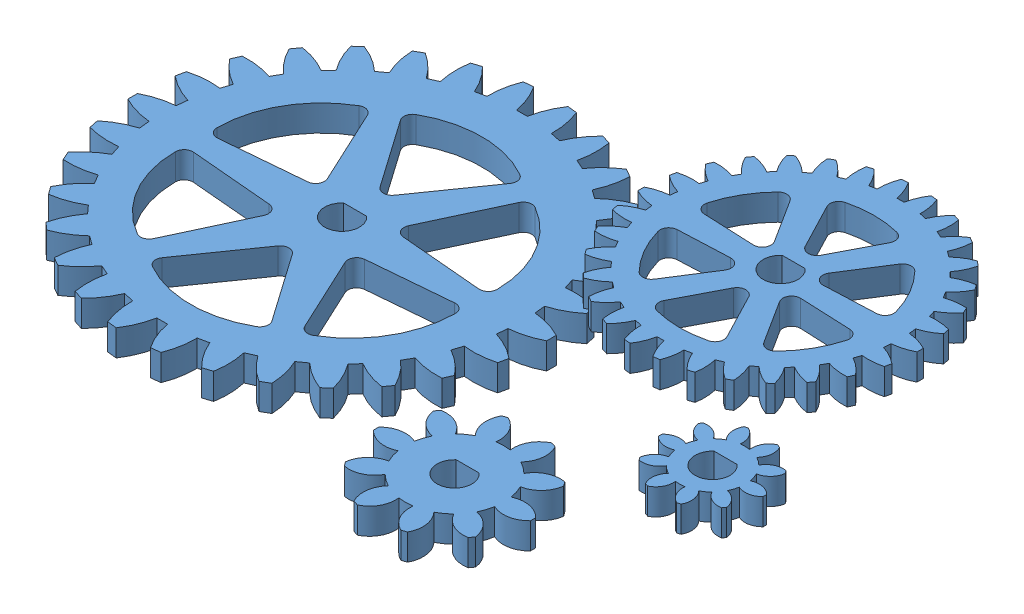
SolidWorks assembly Assem1, configuration Default. Lengths in mm.
Overall size (91.2 18.34 53.96).
4 component instances, 1 part files, 0 mates.
Components (placement in the parent):
- root_gear-1: root_gear [10T 1.5Mod] at (11.6673 10.2824 9.5823) size (18 3 17.3)
- root_gear-2: root_gear [10T 1.0Mod] at (38.5821 23.2654 6.9365) size (12 3 11.53)
- root_gear-3: root_gear [30T 1.0Mod] at (22.0739 22.2953 -17.37) size (32 3 31.89)
- root_gear-4: root_gear [30T 1.5Mod] at (-22.6159 7.9215 -11.8134) size (48 3 47.84)
